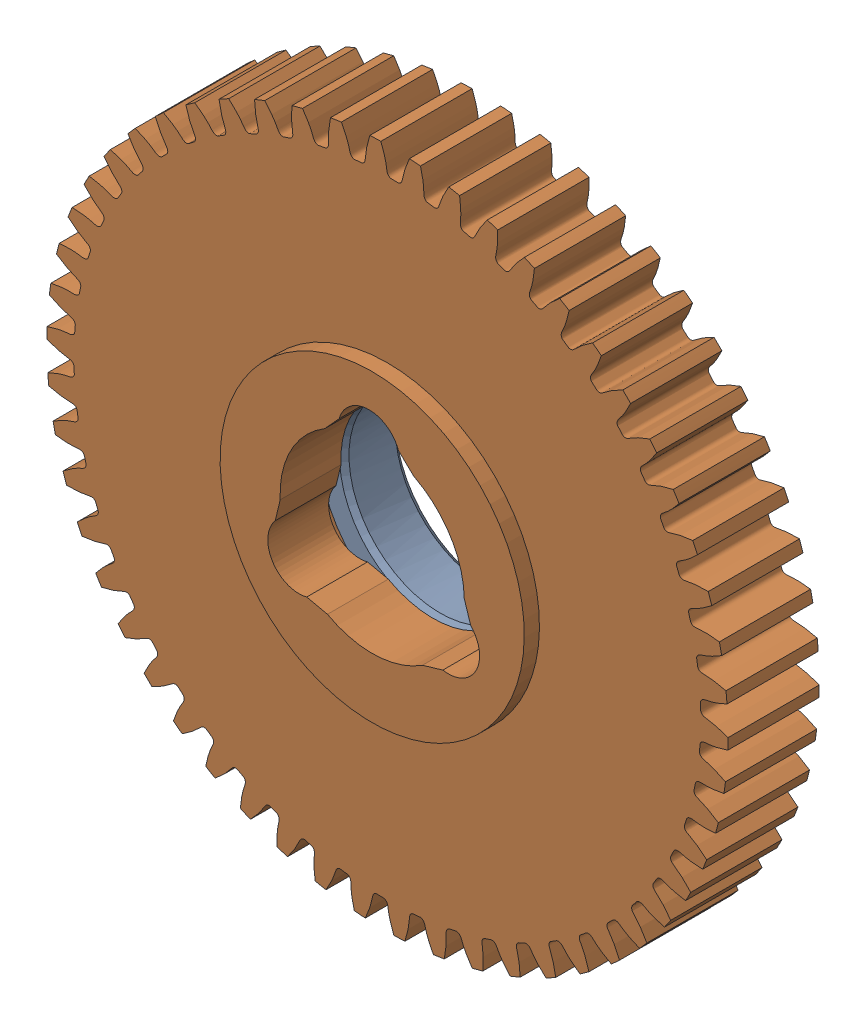
SolidWorks assembly 217-3222-101 Rev1, configuration Default. Lengths in mm.
Overall size (73.87 73.92 12.7).
2 component instances, 2 part files, 0 mates.
Components (placement in the parent):
- 217-2428-022 Rev1-1: 217-2428-022 Rev1 [Default] at (16.3398 14.3476 19.3234) size (28.57 28.57 6.1)
- 217-3222-001 Rev1_Spur01-1: 217-3222-001 Rev1_Spur01 [Default] at (16.3398 14.3476 22.6254) x (0.999377 0.0353 0) z (0 0 1) size (71.39 71.45 11.11)
